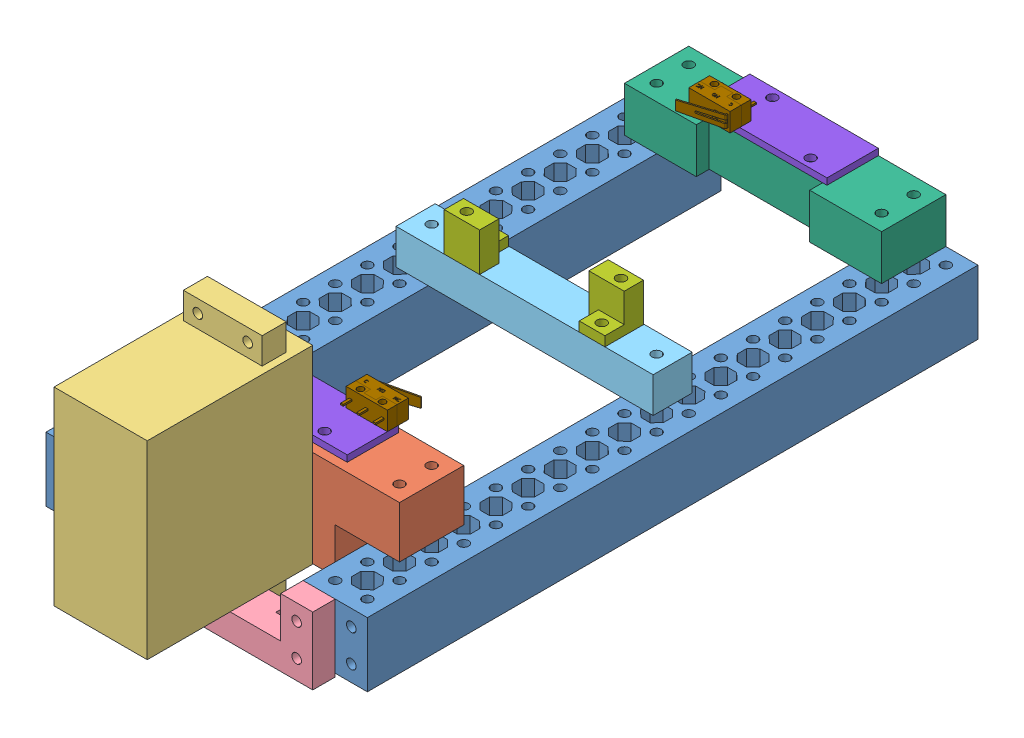
SolidWorks assembly Lift_Model, configuration Default. Lengths in mm.
Overall size (100 75.6 223).
13 component instances, 9 part files, 21 mates.
Components (placement in the parent):
- Beam_Made-1: Beam_Made [Default] at (57.2346 98.7134 46.2914) size (20 20 190)
- servo_holder-1: servo_holder [Default] at (107.2346 104.7134 206.2914) size (80 30 20)
- Beam_Made-2: Beam_Made [Default] at (137.2346 98.7134 46.2914) size (20 20 190)
- BeefyServo-1: BeefyServo [Default] at (92.7346 165.1134 217.7914) x (0 0 1) z (1 0 0) size (53.5 75.4 29)
- BeefyHolder-1: BeefyHolder [Default] at (67.2346 97.7134 236.2914) size (80 21 12)
- slider_made-1: slider_made [Default] at (147.2346 118.7134 125.2064) x (0 0 1) z (-1 0 0) size (12.17 11 80)
- Rear_Screw_Mount_made-1: Rear_Screw_Mount_made [Default] at (67.2346 118.7134 46.2914) size (80 14 20)
- limiters_made-1: limiters_made [Default] at (93.2346 129.7134 137.3764) x (-1 0 0) z (0 0 -1) size (11 12 12)
- limiters_made-2: limiters_made [Default] at (121.2346 129.7134 125.3774) size (11 12 12)
- limit_stand-1: limit_stand [Default] at (86.2346 132.7134 62.2914) size (40 2 16)
- LimitSwitch-1: LimitSwitch [Default] at (92.6596 137.6134 62.0414) x (-1 0 0) z (0 1 0) size (13.2 13.15 6)
- limit_stand-2: limit_stand [Default] at (128.2346 134.7134 197.5714) x (-1 0 0) z (0 0 -1) size (40 2 16)
- LimitSwitch-2: LimitSwitch [Default] at (121.8096 139.6134 197.8214) x (1 0 0) z (0 1 0) size (13.2 13.15 6)
Mates (geometry in assembly coordinates):
- Coincident1: coincident aligned: circle of servo_holder-1; circle of Beam_Made-2
- Coincident6: coincident aligned: circle of servo_holder-1; circle of Beam_Made-2
- Coincident18: coincident aligned: circle of Beam_Made-1; circle of Rear_Screw_Mount_made-1
- Coincident21: coincident aligned: circle of Beam_Made-2; circle of slider_made-1
- Coincident22: coincident aligned: circle of Beam_Made-1; circle of slider_made-1
- Coincident23: coincident aligned: circle of Beam_Made-2; circle of Rear_Screw_Mount_made-1
- Coincident29: coincident aligned: circle of slider_made-1; circle of limiters_made-1
- Parallel3: parallel anti-aligned: line of slider_made-1 through (147.2346 129.7134 137.3774) axis (0 0 -1); line of limiters_made-1 through (93.2346 129.7134 131.3764) axis (0 0 1)
- Coincident31: coincident aligned: circle of slider_made-1; circle of limiters_made-2
- Parallel4: parallel aligned: line of slider_made-1 through (147.2346 129.7134 137.3774) axis (0 0 -1); line of limiters_made-2 through (132.2346 129.7134 137.3774) axis (0 0 -1)
- Coincident33: coincident aligned: circle of Rear_Screw_Mount_made-1; circle of limit_stand-1
- Coincident34: coincident aligned: circle of limit_stand-1; circle of LimitSwitch-1
- Coincident35: coincident anti-aligned: line of limit_stand-1 through (86.2346 134.7134 46.2914) axis (0 0 1); line of LimitSwitch-1 through (86.2346 134.7134 65.2914) axis (0 0 -1)
- Coincident38: coincident aligned: circle of limit_stand-2; circle of LimitSwitch-2
- Coincident39: coincident aligned: circle of servo_holder-1; circle of limit_stand-2
- Parallel5: parallel aligned: line of servo_holder-1 through (147.2346 134.7134 216.2914) axis (0 0 -1); line of limit_stand-2 through (128.2346 136.7134 213.5714) axis (0 0 -1)
- Coincident40: coincident aligned: circle of Beam_Made-1; circle of servo_holder-1
- Coincident47: coincident anti-aligned: circle of Beam_Made-1; circle of BeefyHolder-1
- Coincident48: coincident anti-aligned: circle of Beam_Made-2; circle of BeefyHolder-1
- Coincident51: coincident aligned: circle of BeefyServo-1; circle of BeefyHolder-1
- Coincident52: coincident aligned: circle of BeefyServo-1; circle of BeefyHolder-1
